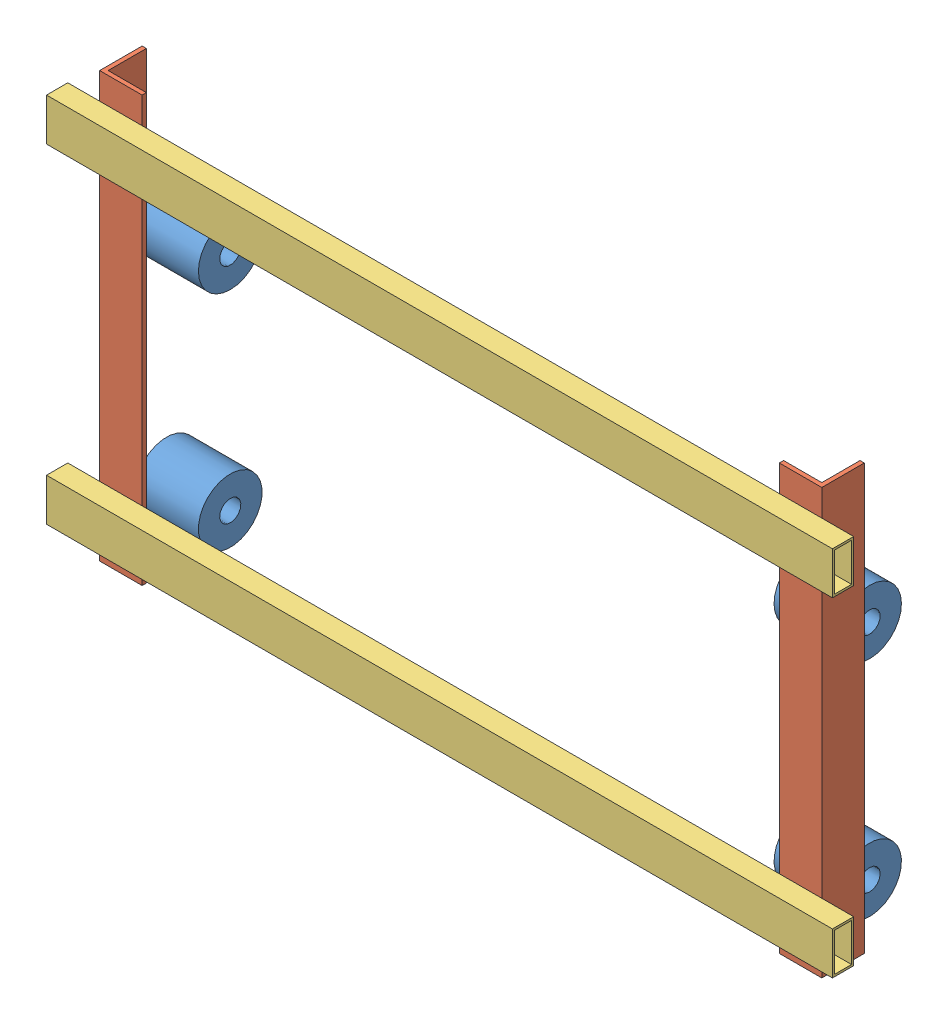
SolidWorks assembly Крюк, configuration По умолчанию. Lengths in mm.
Overall size (740 400 112.97).
8 component instances, 3 part files, 20 mates.
Components (placement in the parent):
- Ролик80-1: Ролик80 [По умолчанию] at (-701 -96.2342 -64) x (0 -0.97484 0.222907) z (0 0.222907 0.97484) size (60 60 60)
- Ролик80-2: Ролик80 [По умолчанию] at (-99 -96.2342 -64) x (0 -0.978497 0.206262) z (0 0.206262 0.978497) size (60 60 60)
- Ролик80-3: Ролик80 [По умолчанию] at (-701 -306.3933 -64) x (0 0.993085 0.117394) z (0 0.117394 -0.993085) size (60 60 60)
- Ролик80-4: Ролик80 [По умолчанию] at (-99 -306.3933 -64) x (0 -0.928943 0.370224) z (0 0.370224 0.928943) size (60 60 60)
- Уголок4040X2-1: Уголок4040X2 [По умолчанию] at (-30 45 -10) x (-1 0 0) z (0 0 1) size (40 400 40)
- Уголок4040X2-2: Уголок4040X2 [По умолчанию] at (-710 -355 -10) size (40 400 40)
- ПрофильП1-1: ПрофильП1 [По умолчанию] x (0 0 -1) z (0 1 0) size (20 740 40)
- ПрофильП1-2: ПрофильП1 [По умолчанию] at (0 -310 0) x (0 0 -1) z (0 1 0) size (20 740 40)
Mates (geometry in assembly coordinates):
- Концентричный1: concentric: cylinder of Ролик80-1 through (-695.7929 -96.2342 -64) axis (-1 0 0) radius 30; cylinder of Ролик80-2 through (-93.7929 -96.2342 -64) axis (-1 0 0) radius 30
- Совпадение3: coincident: plane of Ролик80-1 through (-681 -125.4794 -57.3128) normal (-1 0 0); plane of Ролик80-3 through (-681 -276.6008 -60.4782) normal (-1 0 0)
- Концентричный2: concentric: cylinder of Ролик80-3 through (-695.7929 -306.3933 -64) axis (-1 0 0) radius 30; cylinder of Ролик80-4 through (-93.7929 -306.3933 -64) axis (-1 0 0) radius 30
- Совпадение4: coincident: plane of Ролик80-2 through (-19 -119.1453 -59.1705) normal (1 0 0); plane of Ролик80-4 through (-19 -328.1441 -55.3314) normal (1 0 0)
- Совпадение14: coincident: plane of Уголок4040X2-1 through (-10 45 -10) normal (0 1 0); plane of Уголок4040X2-2 through (-690 45 -10) normal (0 1 0)
- Совпадение15: coincident: plane of Уголок4040X2-1 through (-10 -355 -10) normal (0 0 1); plane of Уголок4040X2-2 through (-690 45 -10) normal (0 0 1)
- Расстояние3: distance = 5 mm: plane of Уголок4040X2-2 through (-706 45 -50) normal (1 0 0); plane of Ролик80-1 through (-701 -125.4794 -57.3128) normal (-1 0 0)
- Расстояние4: distance = 50 mm: cylinder of Ролик80-1 through (-715.7929 -96.2342 -64) axis (-1 0 0) radius 30; plane of Уголок4040X2-2 through (-710 45 -14) normal (0 0 -1)
- Расстояние5: distance = 50 mm: cylinder of Ролик80-3 through (-715.7929 -306.3933 -64) axis (-1 0 0) radius 30; plane of Уголок4040X2-2 through (-710 45 -14) normal (0 0 -1)
- Параллельность2: parallel: plane of ПрофильП1-1 through (-740 -20 -10) normal (0 0 -1); plane of assembly through (0 0 0) normal (0 0 1)
- Совпадение23: coincident: point of ПрофильП1-1; point of assembly
- Параллельность3: parallel: plane of ПрофильП1-1 through (-740 -20 10) normal (0 -1 0); plane of assembly through (0 0 0) normal (0 1 0)
- Совпадение27: coincident: plane of Уголок4040X2-1 through (-10 -355 -10) normal (0 0 1); plane of ПрофильП1-1 through (-740 -20 -10) normal (0 0 -1)
- Расстояние8: distance = 30 mm: plane of Уголок4040X2-1 through (-30 -355 -50) normal (1 0 0); plane of ПрофильП1-1 through (0 0 0) normal (1 0 0)
- Расстояние9: distance = 680 mm: plane of Уголок4040X2-1 through (-30 -355 -50) normal (1 0 0); plane of Уголок4040X2-2 through (-710 45 -50) normal (-1 0 0)
- Расстояние10: distance = 5 mm: plane of Ролик80-2 through (-39 -119.1453 -59.1705) normal (1 0 0); plane of Уголок4040X2-1 through (-34 -355 -50) normal (-1 0 0)
- Расстояние11: distance = 25 mm: plane of Уголок4040X2-2 through (-710 45 -10) normal (0 1 0); plane of ПрофильП1-1 through (-740 20 10) normal (0 1 0)
- Совпадение33: coincident: plane of ПрофильП1-1 through (-740 -20 10) normal (0 0 1); plane of ПрофильП1-2 through (-740 -330 10) normal (0 0 1)
- Совпадение34: coincident: plane of ПрофильП1-1 through (-740 0 0) normal (-1 0 0); plane of ПрофильП1-2 through (-740 -310 0) normal (-1 0 0)
- Расстояние12: distance = 25 mm: plane of ПрофильП1-2 through (-740 -330 10) normal (0 -1 0); plane of Уголок4040X2-2 through (-710 -355 -10) normal (0 -1 0)
